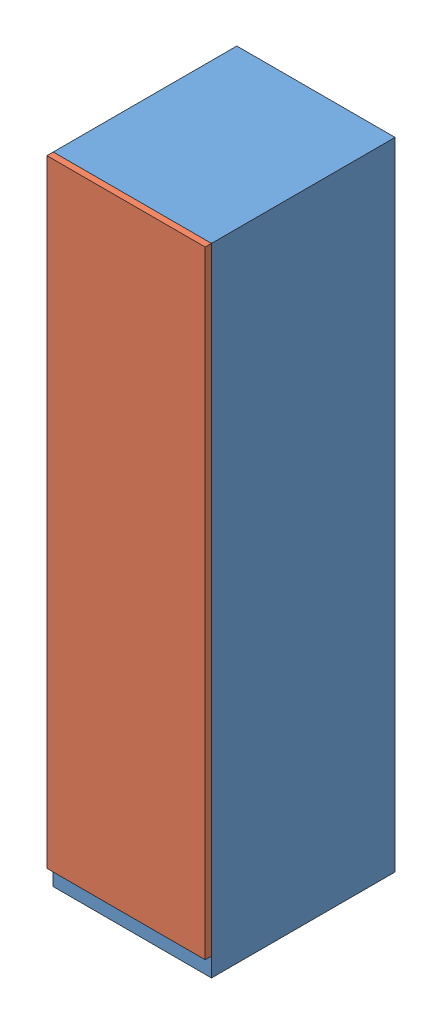
SolidWorks assembly PAX-L, configuration Standard. Lengths in mm.
Overall size (500 2010 600).
7 component instances, 5 part files, 18 mates.
Components (placement in the parent):
- Pax-Korpus-Kleiderschrank-1: Pax-Korpus-Kleiderschrank [Standard] at (-317.8358 -932.7261 1650) size (500 2010 580)
- BALLSTAD-Tür-1: BALLSTAD-Tür [Standard] at (-317.8358 102.2739 1940) size (500 1950 20)
- KOMPLEMENT-Regalbode-1: KOMPLEMENT-Regalbode [Standard] at (-317.8358 -752.7261 1655) size (480 10 570)
- KOMPLIMENT-Schublade-1: KOMPLIMENT-Schublade [Standard] at (-317.8358 -732.7261 1655) size (480 160 570)
- KOMPLEMENT-Regalbode-2: KOMPLEMENT-Regalbode [Standard] at (-317.8358 -562.7261 1655) size (480 10 570)
- KOMPLEMENT-Regalbode-3: KOMPLEMENT-Regalbode [Standard] at (-317.8358 907.2739 1655) size (480 10 570)
- KOMPLEMENT-Kleiderstange-1: KOMPLEMENT-Kleiderstange [Standard] at (-557.8358 692.2739 1660) size (480 50 30)
Mates (geometry in assembly coordinates):
- Deckungsgleich1: coincident anti-aligned: plane of BALLSTAD-Tür-1 through (-317.8358 102.2739 1940) normal (0 0 -1); plane of Pax-Korpus-Kleiderschrank-1 through (-567.8358 -922.7261 1940) normal (0 0 1)
- Deckungsgleich2: coincident aligned: plane of BALLSTAD-Tür-1 through (-567.8358 -872.7261 1960) normal (-1 0 0); plane of Pax-Korpus-Kleiderschrank-1 through (-567.8358 -922.7261 1940) normal (-1 0 0)
- Deckungsgleich3: coincident aligned: plane of BALLSTAD-Tür-1 through (-567.8358 1077.2739 1960) normal (0 1 0); plane of Pax-Korpus-Kleiderschrank-1 through (-317.8358 1077.2739 1650) normal (0 1 0)
- Deckungsgleich4: coincident anti-aligned: plane of Pax-Korpus-Kleiderschrank-1 through (-557.8358 1067.2739 1370) normal (0 0 1); plane of KOMPLEMENT-Regalbode-1 through (-557.8358 -742.7261 1370) normal (0 0 -1)
- Deckungsgleich5: coincident anti-aligned: plane of Pax-Korpus-Kleiderschrank-1 through (-557.8358 1067.2739 1940) normal (1 0 0); plane of KOMPLEMENT-Regalbode-1 through (-557.8358 -742.7261 1940) normal (-1 0 0)
- Abstand1: distance = 120 mm anti-aligned: plane of KOMPLEMENT-Regalbode-1 through (-317.8358 -752.7261 1655) normal (0 -1 0); plane of Pax-Korpus-Kleiderschrank-1 through (-317.8358 -872.7261 1650) normal (0 1 0)
- Deckungsgleich7: coincident anti-aligned: plane of Pax-Korpus-Kleiderschrank-1 through (-557.8358 1067.2739 1370) normal (0 0 1); plane of KOMPLIMENT-Schublade-1 through (-557.8358 -722.7261 1370) normal (0 0 -1)
- Deckungsgleich8: coincident anti-aligned: plane of Pax-Korpus-Kleiderschrank-1 through (-557.8358 1067.2739 1940) normal (1 0 0); plane of KOMPLIMENT-Schublade-1 through (-557.8358 -722.7261 1940) normal (-1 0 0)
- Abstand2: distance = 10 mm anti-aligned: plane of KOMPLEMENT-Regalbode-1 through (-317.8358 -742.7261 1655) normal (0 1 0); plane of KOMPLIMENT-Schublade-1 through (-317.8358 -732.7261 1655) normal (0 -1 0)
- Deckungsgleich10: coincident anti-aligned: plane of Pax-Korpus-Kleiderschrank-1 through (-557.8358 1067.2739 1940) normal (1 0 0); plane of KOMPLEMENT-Regalbode-2 through (-557.8358 -552.7261 1940) normal (-1 0 0)
- Deckungsgleich11: coincident anti-aligned: plane of Pax-Korpus-Kleiderschrank-1 through (-557.8358 1067.2739 1370) normal (0 0 1); plane of KOMPLEMENT-Regalbode-2 through (-557.8358 -552.7261 1370) normal (0 0 -1)
- Abstand3: distance = 10 mm anti-aligned: plane of KOMPLIMENT-Schublade-1 through (-317.8358 -572.7261 1655) normal (0 1 0); plane of KOMPLEMENT-Regalbode-2 through (-317.8358 -562.7261 1655) normal (0 -1 0)
- Deckungsgleich13: coincident anti-aligned: plane of Pax-Korpus-Kleiderschrank-1 through (-557.8358 1067.2739 1940) normal (1 0 0); plane of KOMPLEMENT-Regalbode-3 through (-557.8358 917.2739 1940) normal (-1 0 0)
- Deckungsgleich14: coincident anti-aligned: plane of Pax-Korpus-Kleiderschrank-1 through (-557.8358 1067.2739 1370) normal (0 0 1); plane of KOMPLEMENT-Regalbode-3 through (-557.8358 917.2739 1370) normal (0 0 -1)
- Abstand4: distance = 150 mm anti-aligned: plane of KOMPLEMENT-Regalbode-3 through (-317.8358 917.2739 1655) normal (0 1 0); plane of Pax-Korpus-Kleiderschrank-1 through (-317.8358 1067.2739 1650) normal (0 -1 0)
- Deckungsgleich16: coincident anti-aligned: plane of Pax-Korpus-Kleiderschrank-1 through (-557.8358 1067.2739 1940) normal (1 0 0); plane of KOMPLEMENT-Kleiderstange-1 through (-557.8358 692.2739 1660) normal (-1 0 0)
- Abstand5: distance = 275 mm anti-aligned: plane of KOMPLEMENT-Kleiderstange-1 through (-537.8358 657.2739 1645) normal (0 0 -1); plane of Pax-Korpus-Kleiderschrank-1 through (-557.8358 1067.2739 1370) normal (0 0 1)
- Abstand6: distance = 200 mm anti-aligned: plane of KOMPLEMENT-Kleiderstange-1 through (-537.8358 707.2739 1645) normal (0 1 0); plane of KOMPLEMENT-Regalbode-3 through (-317.8358 907.2739 1655) normal (0 -1 0)
